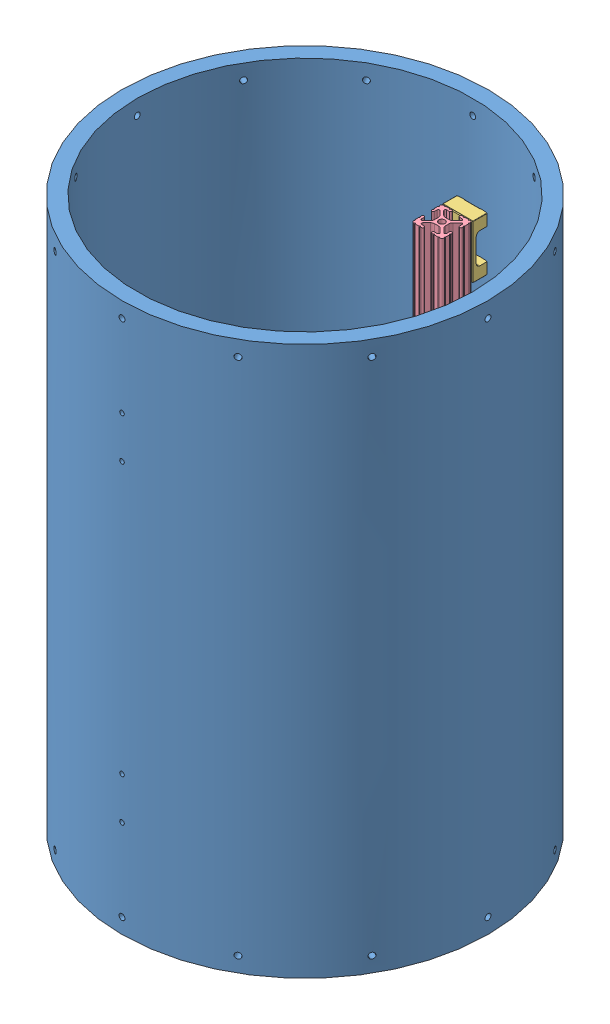
SolidWorks assembly 000048-R01_INTERTANK_AF_ASSM, configuration Default. Lengths in mm.
Overall size (304.8 457.2 304.8).
13 component instances, 4 part files, 6 mates.
Components (placement in the parent):
- 000069-R01_INTERTANK_AF-1: 000069-R01_INTERTANK_AF [Default] at (656.4592 536.0977 -146.471) x (0 0 -1) z (1 0 0) size (304.8 457.2 304.8)
- mount_rail-1: mount_rail [Default] at (675.9995 839.3147 -54.7907) size (25.4 304.8 44.45)
  - 47065T233_ALUMINUM T-SLOTTED FRAMING EXTRUSION-1: 47065T233_ALUMINUM T-SLOTTED FRAMING EXTRUSION [47065T233] at (-19.5403 55.558 33.4144) x (1 0 0) z (0 -1 0) size (14.83 17.81 14.83)
  - extrusion_mount-1: extrusion_mount [Default] at (-19.5403 33.333 44.5269) size (25.4 44.45 19.05)
  - MCMASTER_47065T411_ALUMINUM T-SLOTTED FRAMING EXTRUSION-1: MCMASTER_47065T411_ALUMINUM T-SLOTTED FRAMING EXTRUSION [47065T411] at (-19.5403 -74.617 22.3019) x (1 0 0) z (0 -1 0) size (25.4 25.4 304.8)
  - extrusion_mount-3: extrusion_mount [Default] at (-19.5403 -227.017 44.5269) size (25.4 44.45 19.05)
  - 47065T233_ALUMINUM T-SLOTTED FRAMING EXTRUSION-2: 47065T233_ALUMINUM T-SLOTTED FRAMING EXTRUSION [47065T233] at (-19.5403 -204.792 33.4144) x (1 0 0) z (0 -1 0) size (14.83 17.81 14.83)
- mount_rail-2: mount_rail [Default] at (636.919 839.3147 -238.1512) x (-1 0 0) z (0 0 -1) size (25.4 304.8 44.45)
  - 47065T233_ALUMINUM T-SLOTTED FRAMING EXTRUSION-1: 47065T233_ALUMINUM T-SLOTTED FRAMING EXTRUSION [47065T233] at (-19.5403 55.558 33.4144) x (1 0 0) z (0 -1 0) size (14.83 17.81 14.83)
  - extrusion_mount-1: extrusion_mount [Default] at (-19.5403 33.333 44.5269) size (25.4 44.45 19.05)
  - MCMASTER_47065T411_ALUMINUM T-SLOTTED FRAMING EXTRUSION-1: MCMASTER_47065T411_ALUMINUM T-SLOTTED FRAMING EXTRUSION [47065T411] at (-19.5403 -74.617 22.3019) x (1 0 0) z (0 -1 0) size (25.4 25.4 304.8)
  - extrusion_mount-3: extrusion_mount [Default] at (-19.5403 -227.017 44.5269) size (25.4 44.45 19.05)
  - 47065T233_ALUMINUM T-SLOTTED FRAMING EXTRUSION-2: 47065T233_ALUMINUM T-SLOTTED FRAMING EXTRUSION [47065T233] at (-19.5403 -204.792 33.4144) x (1 0 0) z (0 -1 0) size (14.83 17.81 14.83)
Mates (geometry in assembly coordinates):
- Concentric1: concentric aligned: cylinder of 000069-R01_INTERTANK_AF-1 through (656.4592 651.9852 5.929) axis (0 0 1) radius 1.8986; cylinder of mount_rail-1/extrusion_mount-3 through (656.4592 651.9852 -7.0888) axis (0 0 1) radius 2.0193
- Concentric5: concentric aligned: cylinder of 000069-R01_INTERTANK_AF-1 through (656.4592 617.0602 5.929) axis (0 0 1) radius 1.8986; cylinder of mount_rail-1/extrusion_mount-3 through (656.4592 617.0602 -7.0888) axis (0 0 1) radius 2.0193
- Tangent1: tangent anti-aligned: cylinder of 000069-R01_INTERTANK_AF-1 through (656.4592 993.2977 -146.471) axis (0 -1 0) radius 139.7; cylinder of mount_rail-1/extrusion_mount-3 through (646.9342 656.7477 -3.9138) axis (0 -1 0) radius 3.175
- Concentric7: concentric aligned: cylinder of 000069-R01_INTERTANK_AF-1 through (656.4592 617.0602 -298.871) axis (0 0 -1) radius 1.8986; cylinder of mount_rail-2/extrusion_mount-3 through (656.4592 617.0602 -285.8531) axis (0 0 -1) radius 2.0193
- Concentric8: concentric aligned: cylinder of 000069-R01_INTERTANK_AF-1 through (656.4592 651.9852 -298.871) axis (0 0 -1) radius 1.8986; cylinder of mount_rail-2/extrusion_mount-3 through (656.4592 651.9852 -285.8531) axis (0 0 -1) radius 2.0193
- Tangent3: tangent anti-aligned: cylinder of 000069-R01_INTERTANK_AF-1 through (656.4592 993.2977 -146.471) axis (0 -1 0) radius 139.7; cylinder of mount_rail-2/extrusion_mount-3 through (665.9842 656.7477 -289.0281) axis (0 -1 0) radius 3.175
